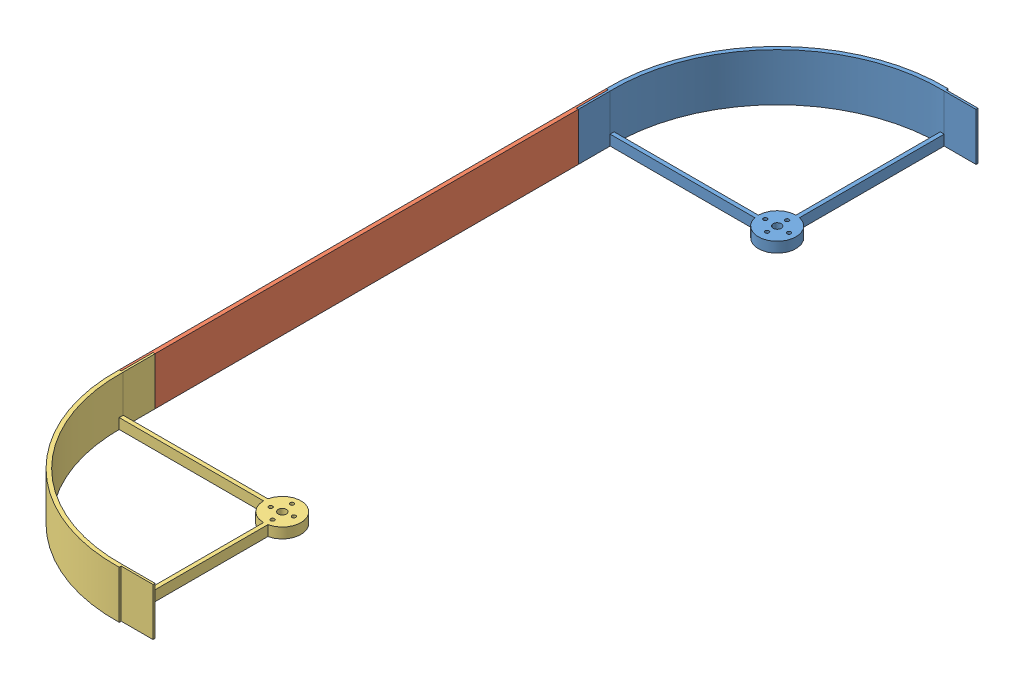
SolidWorks assembly Assem3, configuration Default. Lengths in mm.
Overall size (161.92 38.1 661.67).
3 component instances, 3 part files, 6 mates.
Components (placement in the parent):
- PropGuard1-1: PropGuard1 [Default] at (93.2963 43.727 134.6561) size (161.92 38.1 161.92)
- flatGuard-1: flatGuard [Default] at (-40.0154 43.727 137.8311) x (0 0 1) z (-1 0 0) size (388.62 38.1 3.17)
- PropGuard2-1: PropGuard2 [Default] at (93.2963 43.727 529.6261) x (0 0 -1) z (1 0 0) size (161.92 38.1 161.92)
Mates (geometry in assembly coordinates):
- Coincident1: coincident: plane of PropGuard1-1 through (-38.4279 81.827 163.2311) normal (-1 0 0); plane of flatGuard-1 through (-38.4279 81.827 137.8311) normal (1 0 0)
- Coincident2: coincident: plane of PropGuard1-1 through (93.2963 81.827 134.6561) normal (0 1 0); plane of flatGuard-1 through (-40.0154 81.827 137.8311) normal (0 1 0)
- Coincident3: coincident anti-aligned: plane of PropGuard1-1 through (93.2963 43.727 163.2311) normal (0 0 1); plane of flatGuard-1 through (-38.4279 81.827 163.2311) normal (0 0 -1)
- Coincident4: coincident: plane of flatGuard-1 through (-38.4279 81.827 526.4511) normal (1 0 0); plane of PropGuard2-1 through (-38.4279 81.827 501.0511) normal (-1 0 0)
- Coincident5: coincident: plane of flatGuard-1 through (-38.4279 81.827 501.0511) normal (0 0 1); plane of PropGuard2-1 through (93.2963 43.727 501.0511) normal (0 0 -1)
- Coincident6: coincident aligned: plane of flatGuard-1 through (-40.0154 81.827 137.8311) normal (0 1 0); plane of PropGuard2-1 through (93.2963 81.827 529.6261) normal (0 1 0)
